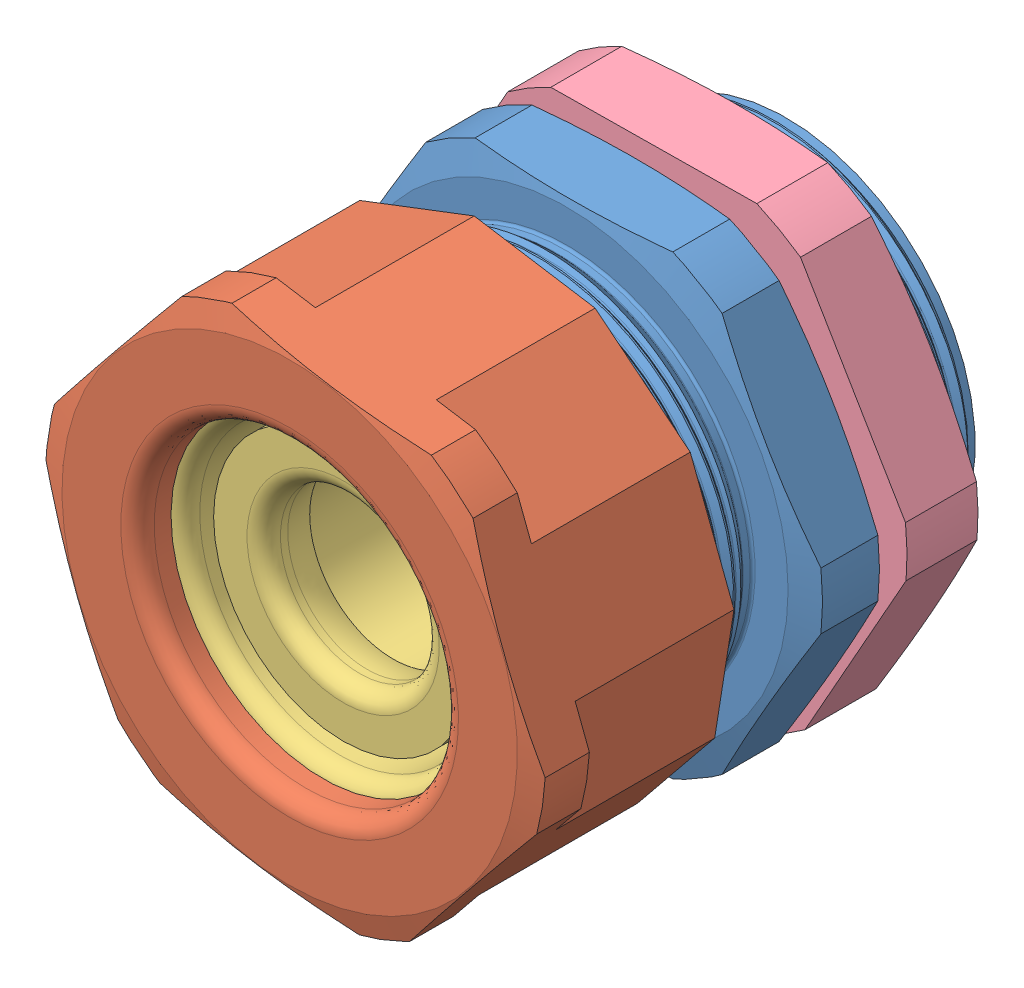
SolidWorks assembly Cable Gland, configuration 00. Lengths in mm.
Overall size (67.68 63.44 59.43).
4 component instances, 4 part files, 4 mates.
Components (placement in the parent):
- Cable Gland^Cable Gland-1: Cable Gland^Cable Gland [00] at origin size (59.5 54.6 44.01) (virtual)
- Pressure Nut^Cable Gland-1: Pressure Nut^Cable Gland [00] at (0 0 37.4175) x (0.987492 -0.15767 0) z (0 0 1) size (59.8 54.7 25.75) (virtual)
- Insert Neopren^Cable Gland-1: Insert Neopren^Cable Gland [00] at (0 0 33.4175) size (43.5 43.5 22.4) (virtual)
- LockNut^Cable Gland-1: LockNut^Cable Gland [00] at (0 0 -6.4519) x (-0.99994 -0.010934 0) z (0 0 -1) size (60 54.7 10.58) (virtual)
Mates (geometry in assembly coordinates):
- Концентричный1: concentric anti-aligned: cylinder of Cable Gland^Cable Gland-1 through (0 0 20.7) axis (0 0 1) radius 22.6; cylinder of Pressure Nut^Cable Gland-1 through (0 0 33.4175) axis (0 0 -1) radius 22.75
- Концентричный2: concentric anti-aligned: cone of Cable Gland^Cable Gland-1 through (0 0 0) axis (0 0 -1); cylinder of Insert Neopren^Cable Gland-1 through (0 0 56.455) axis (0 0 1) radius 16.75
- Совпадение1: coincident anti-aligned: plane of Pressure Nut^Cable Gland-1 through (0 0 33.4175) normal (0 0 -1); plane of Insert Neopren^Cable Gland-1 through (18.75 0 33.4175) normal (0 0 1)
- Концентричный3: concentric aligned: cylinder of Cable Gland^Cable Gland-1 through (0 0 22) axis (0 0 -1) radius 23.5; cylinder of LockNut^Cable Gland-1 through (0 0 -6.4519) axis (0 0 -1) radius 22.75
